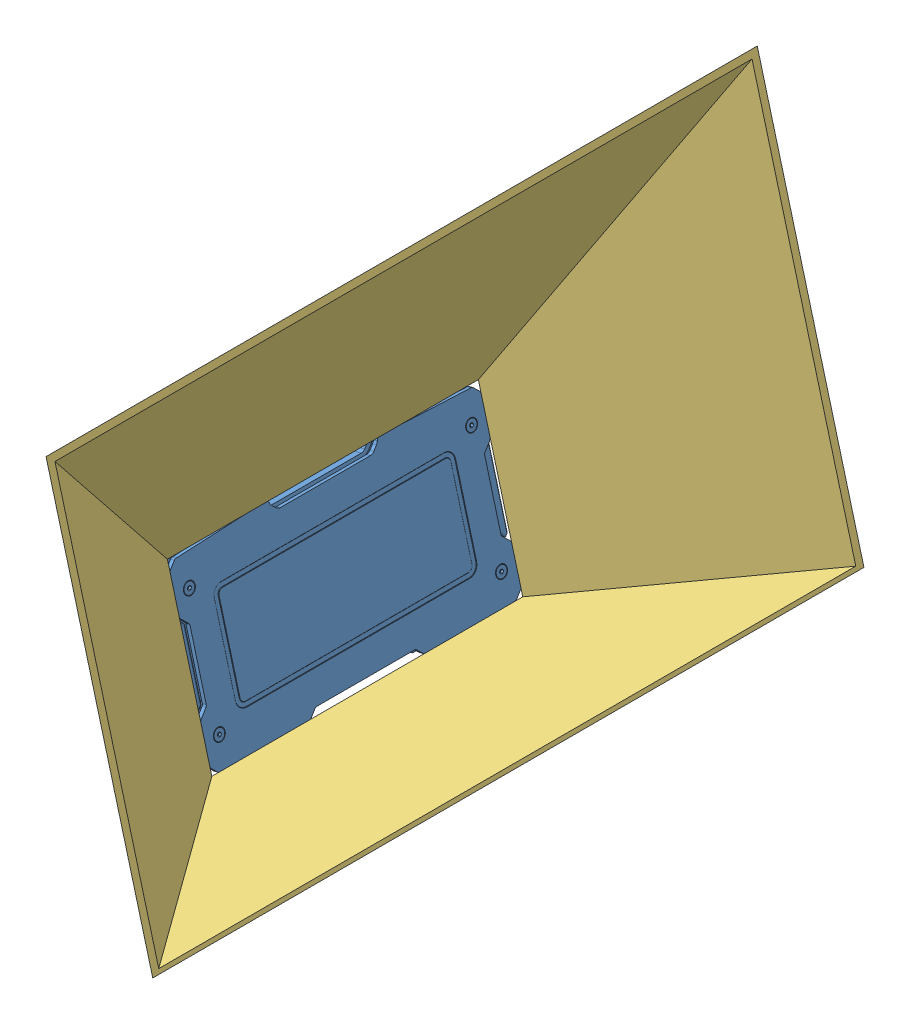
SolidWorks assembly 装甲板-装配-大, configuration 安装要求. Lengths in mm.
Overall size (212.65 320.44 526.09).
4 component instances, 3 part files, 9 mates.
Components (placement in the parent):
- 装甲板-大-1: 装甲板-大 [默认] at (-92.9917 163.9656 -92.5044) x (0.258819 0.965926 0) z (0 0 -1) size (119.56 81.32 236)
- 装甲板-支架-2: 装甲板-支架 [默认] at (58.5 -1.5 0) x (0 0 -1) z (0.965926 0.258819 0) size (15 130.97 68.39)
- 装甲板-安装要求-大-1: 装甲板-安装要求-大 [默认] at (71.0922 24.9158 -47.5) x (0 0 -1) z (0.258819 -0.965926 0) size (526.09 100 304.95)
- 装甲板-支架-5: 装甲板-支架 [默认] at (58.5 -1.5 -95) x (0 0 -1) z (0.965926 0.258819 0) size (15 130.97 68.39)
Mates (geometry in assembly coordinates):
- 重合4: coincident anti-aligned: plane of RM-装甲板大-1 through (35.242 85.3 -87.5) normal (0 1 0); plane of RM-装甲板支架-2 through (35.242 85.3 21.6193) normal (0 -1 0)
- 重合9: coincident anti-aligned: plane of RM-装甲板大-1 through (53.0269 18.926 -47.5) normal (-0.965926 -0.258819 0); plane of RM-装甲板支架-2 through (35.2063 85.4333 -7.5) normal (0.965926 0.258819 0)
- 重合7: coincident anti-aligned: plane of RM-装甲板大-1 through (71.3769 23.8533 -47.5) normal (0.965926 0.258819 0); plane of 装甲安装要求-大-1 through (71.0922 24.9158 -47.5) normal (-0.965926 -0.258819 0)
- 对称1: symmetric aligned: plane of RM-装甲板大-1 through (87.5531 -36.5171 67.5) normal (0 0 1); plane of 装甲安装要求-大-1 through (87.5531 -36.5171 -162.5) normal (0 0 -1); plane of RM-装甲板大-1 through (71.0922 24.9158 -47.5) normal (0 0 -1)
- 对称2: symmetric aligned: plane of RM-装甲板大-1 through (-22.6179 65.6498 -47.5) normal (-0.258819 0.965926 0); plane of 装甲安装要求-大-1 through (87.5531 -36.5171 67.5) normal (0.258819 -0.965926 0); plane of RM-装甲板大-1 through (71.0922 24.9158 -47.5) normal (0.258819 -0.965926 0)
- 宽度1: width anti-aligned: plane of RM-装甲板大-1 through (75.4739 -20.4148 -8) normal (0 0 1); plane of RM-装甲板支架-2 through (75.4739 -20.4148 8) normal (0 0 -1); plane of RM-装甲板大-1 through (58.5 -1.5 -7.5) normal (0 0 -1); plane of RM-装甲板支架-2 through (58.5 -1.5 7.5) normal (0 0 1)
- 重合10: coincident anti-aligned: plane of RM-装甲板大-1 through (35.242 85.3 -87.5) normal (0 1 0); plane of RM-装甲板支架-5 through (35.242 85.3 -73.3807) normal (0 -1 0)
- 重合11: coincident anti-aligned: plane of RM-装甲板大-1 through (53.0269 18.926 -47.5) normal (-0.965926 -0.258819 0); plane of RM-装甲板支架-5 through (35.2063 85.4333 -102.5) normal (0.965926 0.258819 0)
- 宽度2: width anti-aligned: plane of RM-装甲板大-1 through (75.4739 -20.4148 -87) normal (0 0 -1); plane of RM-装甲板支架-5 through (75.4739 -20.4148 -103) normal (0 0 1); plane of RM-装甲板大-1 through (58.5 -1.5 -102.5) normal (0 0 -1); plane of RM-装甲板支架-5 through (58.5 -1.5 -87.5) normal (0 0 1)
